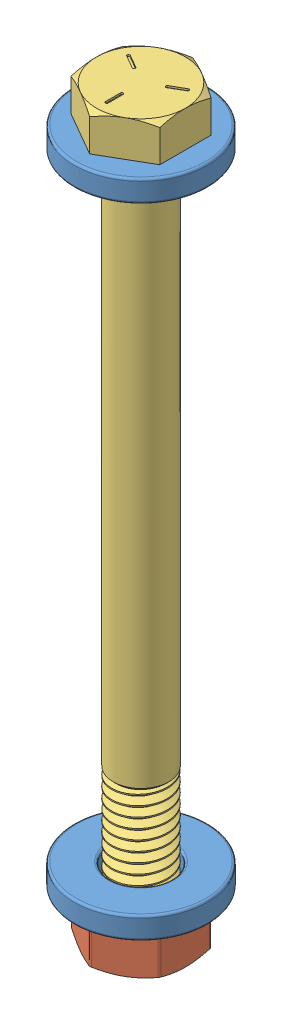
SolidWorks assembly t_slot_motorscrew_assembly, configuration Default. Lengths in mm.
Overall size (26.37 107.28 26.37).
4 component instances, 3 part files, 10 mates.
Components (placement in the parent):
- 5-16x.75 oversize washer 91525A326_316 Stainless Steel Washer-3: 5-16x.75 oversize washer 91525A326_316 Stainless Steel Washer [91525A326] at (0 1.5875 0) x (0.837169 0 0.546944) z (0 1 0) size (19.05 19.05 3.17)
- 5-16x.75 oversize washer 91525A326_316 Stainless Steel Washer-4: 5-16x.75 oversize washer 91525A326_316 Stainless Steel Washer [91525A326] at (0 -89.5875 0) x (1 0 0) z (0 -1 0) size (19.05 19.05 3.17)
- 5-18 nut 95462A030_Medium-Strength Steel Hex Nut(1)-1: 5-18 nut 95462A030_Medium-Strength Steel Hex Nut(1) [95462A030] at (0 -94.5484 0) x (0.5 0 -0.866025) z (0 1 0) size (12.7 14.57 7.61)
- 5s16p18x4 bolt 91247A599_Medium-Strength Grade 5 Steel Hex Head Screw-1: 5s16p18x4 bolt 91247A599_Medium-Strength Grade 5 Steel Hex Head Screw [91247A599] at (0 -45.0453 0) x (0 -1 0) z (-1 0 0) size (107.28 14.66 12.7)
Mates (geometry in assembly coordinates):
- Concentric1: concentric aligned: cylinder of 5-16x.75 oversize washer 91525A326_316 Stainless Steel Washer-3 through (0 0 0) axis (0 1 0) radius 4.3688
- Coincident8: coincident anti-aligned: plane of 5-16x.75 oversize washer 91525A326_316 Stainless Steel Washer-3 through (0 0 0) normal (0 -1 0)
- Concentric2: concentric anti-aligned: cylinder of 5-16x.75 oversize washer 91525A326_316 Stainless Steel Washer-3 through (0 0 0) axis (0 1 0) radius 4.3688; cylinder of 5-16x.75 oversize washer 91525A326_316 Stainless Steel Washer-4 through (0 -88 0) axis (0 -1 0) radius 4.3688
- Distance1: distance anti-aligned: plane of 5-16x.75 oversize washer 91525A326_316 Stainless Steel Washer-4 through (0 -88 0) normal (0 1 0); plane of 5-16x.75 oversize washer 91525A326_316 Stainless Steel Washer-3 through (0 0 0) normal (0 -1 0)
- Coincident12: coincident anti-aligned: plane of 5-16x.75 oversize washer 91525A326_316 Stainless Steel Washer-4 through (0 -91.175 0) normal (0 -1 0); plane of 5-18 nut 95462A030_Medium-Strength Steel Hex Nut(1)-1 through (0 -91.175 0) normal (0 1 0)
- Concentric4: concentric anti-aligned: circle of 5-16x.75 oversize washer 91525A326_316 Stainless Steel Washer-4; circle of 5-18 nut 95462A030_Medium-Strength Steel Hex Nut(1)-1
- Coincident14: coincident aligned: plane of 5-16x.75 oversize washer 91525A326_316 Stainless Steel Washer-4 through (0 -89.5875 0) normal (1 0 0)
- Concentric5: concentric anti-aligned: cylinder of 5-16x.75 oversize washer 91525A326_316 Stainless Steel Washer-3 through (0 0 0) axis (0 1 0) radius 4.3688; cylinder of 5s16p18x4 bolt 91247A599_Medium-Strength Grade 5 Steel Hex Head Screw-1 through (0 3.175 0) axis (0 -1 0) radius 3.9688
- Coincident15: coincident anti-aligned: plane of 5-16x.75 oversize washer 91525A326_316 Stainless Steel Washer-3 through (0 3.175 0) normal (0 1 0); plane of 5s16p18x4 bolt 91247A599_Medium-Strength Grade 5 Steel Hex Head Screw-1 through (-6.35 3.175 3.6662) normal (0 -1 0)
- Parallel1: parallel anti-aligned: plane of 5s16p18x4 bolt 91247A599_Medium-Strength Grade 5 Steel Hex Head Screw-1 through (-6.35 8.3344 -3.6662) normal (-1 0 0)
